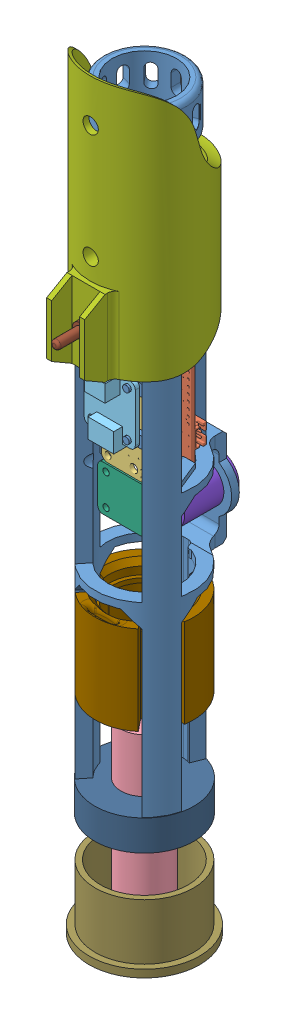
SolidWorks assembly Lightsaber, configuration Default. Lengths in mm.
Overall size (43.52 303.44 64.9).
16 component instances, 16 part files, 36 mates.
Components (placement in the parent):
- rough_size-1: rough_size [Default] at origin size (42.72 300 21.36) (hidden)
- blade-1: blade [Default] at (0 230 0) size (25.4 1016 25.4) (hidden)
- chassis-1: chassis [Default] at (0 125.5969 0) size (38.72 248.9 45.76)
- 3857 Adafruit Feather M4 Express-1: 3857 Adafruit Feather M4 Express [Default] at (-11.425 155.5969 -7) x (0 1 0) z (0 0 -1) size (50.85 22.86 6.37)
- 3988 Prop-Maker FeatherWing-1: 3988 Prop-Maker FeatherWing [Default] at (-11.425 155.5969 5.5) x (0 1 0) z (0 0 -1) size (50.8 22.86 6.37)
- battery-1: battery [Default] at (0 2.3879 0) size (18.42 68.7 18.42)
- charging board-1: charging board [Default] at (0 184.7158 12) x (-1 0 0) z (0 1 0) size (20.14 7.55 24.64)
- gyro board-1: gyro board [Default] at (-0.675 144.5969 5.5) x (0 -1 0) z (1 0 0) size (17.82 5 25.62)
- opening1-1: opening1 [Default] at (0 230 0) size (42.72 100.44 52.36)
- button-1: button [Default] at (0 139.4983 -8) x (1 0 0) z (0 1 0) size (15.78 21.4 15.78)
- speaker-1: speaker [Default] at (0 109.3173 0) x (0.99564 0 0.093282) z (-0.093282 0 0.99564) size (27.83 2.2 27.83) (hidden)
- handle-1: handle [Default] at origin size (46.72 120 46.72) (hidden)
- speaker_housing-1: speaker_housing [Default] at (0 79.3173 0) size (38.72 35.24 37.54)
- battery holder-1: battery holder [Default] at (0 40 0) size (39.05 12 39.05)
- switch-2: switch [Default] at (0 215.0319 6.5) x (0 -1 0) z (-1 0 0) size (12.8 35 6.92)
- End_Cap^Lightsaber-1: End_Cap^Lightsaber [Default] x (-1 0 0) z (0 -1 0) size (43.52 43.52 25) (virtual)
Mates (geometry in assembly coordinates):
- Concentric1: concentric: cylinder of rough_size-1 through (0 300 0) axis (0 -1 0) radius 17.36; cylinder of blade-1 through (0 1246 0) axis (0 -1 0) radius 12.7
- Distance2: distance = 70 mm: plane of rough_size-1 through (0 300 0) normal (0 1 0); plane of blade-1 through (0 230 0) normal (0 -1 0)
- Coincident3: coincident: plane of chassis-1 through (0 125.5969 0) normal (0 0 1); plane of assembly through (0 0 0) normal (0 0 1)
- Coincident4: coincident: plane of chassis-1 through (0 125.5969 0) normal (1 0 0); plane of assembly through (0 0 0) normal (1 0 0)
- Coincident5: coincident: plane of 3857 Adafruit Feather M4 Express-1 through (-11.425 155.5969 -7) normal (1 0 0); plane of 3988 Prop-Maker FeatherWing-1 through (-11.425 155.5969 5.5) normal (1 0 0)
- Coincident6: coincident: plane of 3857 Adafruit Feather M4 Express-1 through (-11.425 155.5969 -7) normal (0 1 0); plane of 3988 Prop-Maker FeatherWing-1 through (-11.425 155.5969 5.5) normal (0 1 0)
- Distance4: distance = 12.5 mm: plane of 3857 Adafruit Feather M4 Express-1 through (-11.425 155.5969 -7) normal (0 0 -1); plane of 3988 Prop-Maker FeatherWing-1 through (-11.425 155.5969 5.5) normal (0 0 -1)
- Parallel2: parallel: plane of 3857 Adafruit Feather M4 Express-1 through (-11.425 155.5969 -7) normal (0 0 -1); plane of assembly through (0 0 0) normal (0 0 1)
- Coincident11: coincident: plane of 3988 Prop-Maker FeatherWing-1 through (-11.425 155.5969 5.5) normal (0 0 -1); plane of gyro board-1 through (-0.675 144.5969 5.5) normal (0 0 -1)
- Distance7: distance = 7 mm: plane of 3857 Adafruit Feather M4 Express-1 through (-11.425 155.5969 -7) normal (0 0 -1); plane of chassis-1 through (0 125.5969 0) normal (0 0 1)
- Distance8: distance = 30 mm: plane of chassis-1 through (0 125.5969 0) normal (0 1 0); plane of 3857 Adafruit Feather M4 Express-1 through (-11.425 155.5969 -7) normal (0 1 0)
- Distance9: distance = 11.425 mm: plane of chassis-1 through (0 125.5969 0) normal (1 0 0); plane of 3857 Adafruit Feather M4 Express-1 through (-11.425 155.5969 -7) normal (1 0 0)
- Distance10: distance = 11 mm: plane of 3857 Adafruit Feather M4 Express-1 through (-11.425 155.5969 -7) normal (0 1 0); plane of gyro board-1 through (-0.675 144.5969 5.5) normal (0 -1 0)
- Distance11: distance = 10.75 mm: plane of 3857 Adafruit Feather M4 Express-1 through (-11.425 155.5969 -7) normal (1 0 0); plane of gyro board-1 through (-0.675 144.5969 5.5) normal (1 0 0)
- Concentric2: concentric: cylinder of blade-1 through (0 1246 0) axis (0 -1 0) radius 12.7; cylinder of opening1-1 through (0 300 0) axis (0 -1 0) radius 17.36
- Concentric3: concentric: cylinder of rough_size-1 through (0 300 0) axis (0 -1 0) radius 17.36; cylinder of battery-1 through (0 71.0879 0) axis (0 -1 0) radius 9.21
- Distance14: distance = 12 mm: plane of chassis-1 through (0 125.5969 0) normal (0 0 1); plane of charging board-1 through (0 184.7158 12) normal (0 0 1)
- Distance15: distance = 125.5969 mm: plane of chassis-1 through (0 125.5969 0) normal (0 1 0); plane of assembly through (0 0 0) normal (0 1 0)
- Distance16: distance = 8 mm: plane of button-1 through (0 139.4983 -8) normal (0 0 -1); plane of assembly through (0 0 0) normal (0 0 1)
- Coincident24: coincident: plane of button-1 through (0 139.4983 -8) normal (1 0 0); plane of assembly through (0 0 0) normal (1 0 0)
- Distance17: distance = 0 mm: plane of charging board-1 through (0 184.7158 12) normal (-1 0 0); plane of assembly through (0 0 0) normal (1 0 0)
- Concentric4: concentric: cylinder of chassis-1 through (0 40 0) axis (0 1 0) radius 14.36; cylinder of speaker-1 through (0 111.5173 0) axis (0 -1 0) radius 13.915
- Concentric5: concentric: cylinder of chassis-1 through (0 40 0) axis (0 1 0) radius 19.36; cylinder of handle-1 through (0 120 0) axis (0 -1 0) radius 19.36
- Coincident26: coincident: plane of rough_size-1 through (0 0 0) normal (0 -1 0); plane of handle-1 through (0 0 0) normal (0 -1 0)
- Concentric6: concentric: cylinder of chassis-1 through (0 40 0) axis (0 1 0) radius 14.36; cylinder of speaker_housing-1 through (0 109.3173 0) axis (0 -1 0) radius 12.5
- Coincident27: coincident: plane of speaker_housing-1 through (0 79.3173 0) normal (0 0 1); plane of assembly through (0 0 0) normal (0 0 1)
- Coincident30: coincident: plane of opening1-1 through (0 230 0) normal (0 0 1); plane of assembly through (0 0 0) normal (0 0 1)
- Coincident32: coincident: plane of switch-2 through (0 215.0319 6.5) normal (-1 0 0); plane of assembly through (0 0 0) normal (1 0 0)
- Concentric8: concentric: cylinder of opening1-1 through (0 215.0319 -21.361) axis (0 0 1) radius 2.88; cylinder of switch-2 through (0 215.0319 25.5) axis (0 0 -1) radius 2.88
- Coincident33: coincident: plane of speaker-1 through (0 109.3173 0) normal (0 -1 0); plane of speaker_housing-1 through (0 109.3173 0) normal (0 1 0)
- Concentric9: concentric: cylinder of chassis-1 through (0 40 0) axis (0 1 0) radius 19.36; cylinder of speaker_housing-1 through (0 109.3173 0) axis (0 -1 0) radius 19.36
- Concentric10: concentric: cylinder of blade-1 through (0 1246 0) axis (0 -1 0) radius 12.7; cylinder of chassis-1 through (0 40 0) axis (0 1 0) radius 14.36
- InPlace1: in place: plane of ? through (0 0 0) normal (0 -1 0); plane of End_Cap^Lightsaber-1 through (0 0 0) normal (0 -1 0); moOrthogonalPlaneRef_w of ? through (0 0 0) normal (0 -1 0); plane of End_Cap^Lightsaber-1 through (0 0 0) normal (0 0 -1); plane of ? through (0 0 0) normal (0 -1 0); plane of End_Cap^Lightsaber-1 through (0 0 0) normal (-1 0 0); plane of ? through (0 0 0) normal (0 -1 0); unknown of End_Cap^Lightsaber-1
- Coincident34: coincident: plane of handle-1; plane of End_Cap^Lightsaber-1
- Coincident35: coincident: moOrthogonalPlaneRef_w of handle-1 through (0 0 0) normal (0 0 -1); plane of End_Cap^Lightsaber-1 through (0 0 0) normal (0 0 -1)
- Coincident36: coincident: moOrthogonalPlaneRef_w of handle-1 through (0 0 0) normal (1 0 0); plane of End_Cap^Lightsaber-1 through (0 0 0) normal (-1 0 0)
